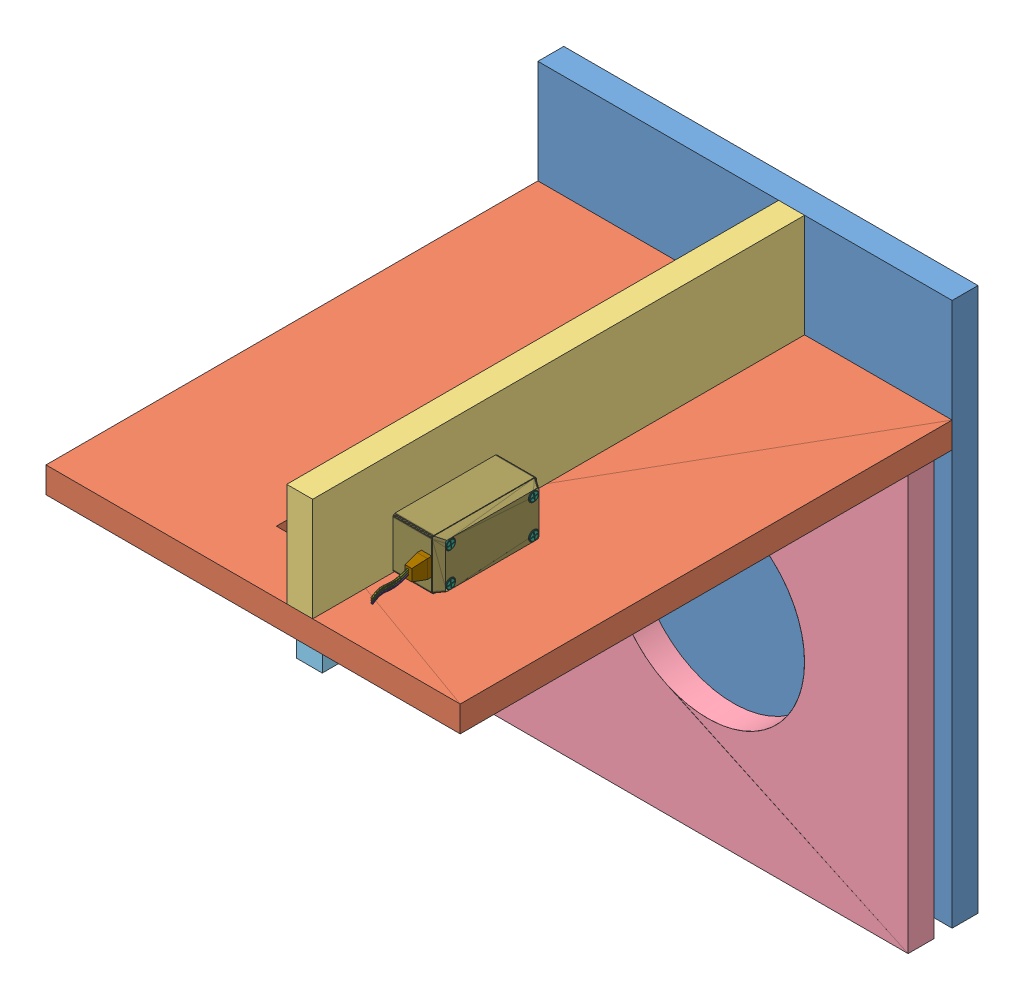
SolidWorks assembly cup_holder, configuration Standard. Lengths in mm.
Overall size (4064 5334 5080).
25 component instances, 14 part files, 0 mates.
Components (placement in the parent):
- Basis-1: Basis [Standard] at (44270.4588 20217.1899 127) size (4064 5334 254)
- Wall-1: Wall [Standard] at (44270.4588 21741.1443 2667) size (4064 253.91 4826)
- Servo_holder-1: Servo_holder [Standard] at (44727.6588 22376.0986 2667) size (254 1016 4826)
- Glass_holder-1: Glass_holder [Standard] at (44270.4588 19582.1899 558.8) size (4064 4064 254)
- Dispenser-1: Dispenser [Standard] at (44245.0588 21055.3899 4245.483) size (254 355.6 515.37)
- Servo_HITEC_HS645MG-1: Servo_HITEC_HS645MG [Standard] at (44760.6957 22039.4494 3954.7475) x (0 0 1) z (-1 0 0) size (1737.81 803.79 1114.29)
  - Groupe_5-1: Groupe_5 [Standard] at origin size (1737.81 803.79 1114.29)
    - Groupe_6-1: Groupe_6 [Standard] at (231.2826 -91.8146 -539.1957) size (90.82 90.82 35.9)
      - Groupe_7-1: Groupe_7 [Standard] at origin size (90.82 90.82 35.9)
    - Groupe_6-2: Groupe_6 [Standard] at (231.2826 243.4654 -539.1957) size (90.82 90.82 35.9)
      - Groupe_7-1: Groupe_7 [Standard] at origin size (90.82 90.82 35.9)
    - Groupe_4-1: Groupe_4 [Standard] at (603.3792 69.1313 -424.1632) x (0 0 -1) z (1 0 0) size (101.7 178.59 531.1)
      - Groupe_8-1: Groupe_8 [Standard] at (-10.9872 -23.8269 84.5461) x (0 1 0) z (-1 0 0) size (130.89 361.96 18.8)
        - Groupe_8-1-1: Groupe_8-1 [Standard] at origin size (109.27 361.96 18.8)
        - Groupe_8-2-1: Groupe_8-2 [Standard] at origin size (88.6 361.96 18.8)
      - Groupe_8-2: Groupe_8 [Standard] at (-10.9872 -23.8269 84.5461) x (0 1 0) z (-1 0 0) size (130.89 361.96 18.8)
      - Groupe_4-1: Groupe_4 [Standard] at origin size (101.7 177.9 175.36)
    - Groupe_1-1: Groupe_1 [Standard] at (54.7631 76.0827 474.1397) size (330.2 330.2 134.62)
    - Groupe_6-3: Groupe_6 [Standard] at (-586.5974 243.4654 -539.1957) size (90.82 90.82 35.9)
      - Groupe_7-1: Groupe_7 [Standard] at origin size (90.82 90.82 35.9)
    - Groupe_6-4: Groupe_6 [Standard] at (-586.5974 -91.8146 -539.1957) size (90.82 90.82 35.9)
      - Groupe_7-1: Groupe_7 [Standard] at origin size (90.82 90.82 35.9)
    - Group_5-1: Group_5 [Standard] at (-31.4317 -78.1778 502.3083) x (0.866859 -0.498554 0) z (0 0 1) size (230.22 579.89 109.68)
    - Groupe_5-1: Groupe_5 [Standard] at origin size (1384.82 652.46 957.99)
- cup_holder-1: cup_holder [Standard] at origin size (1905 1905 0)
